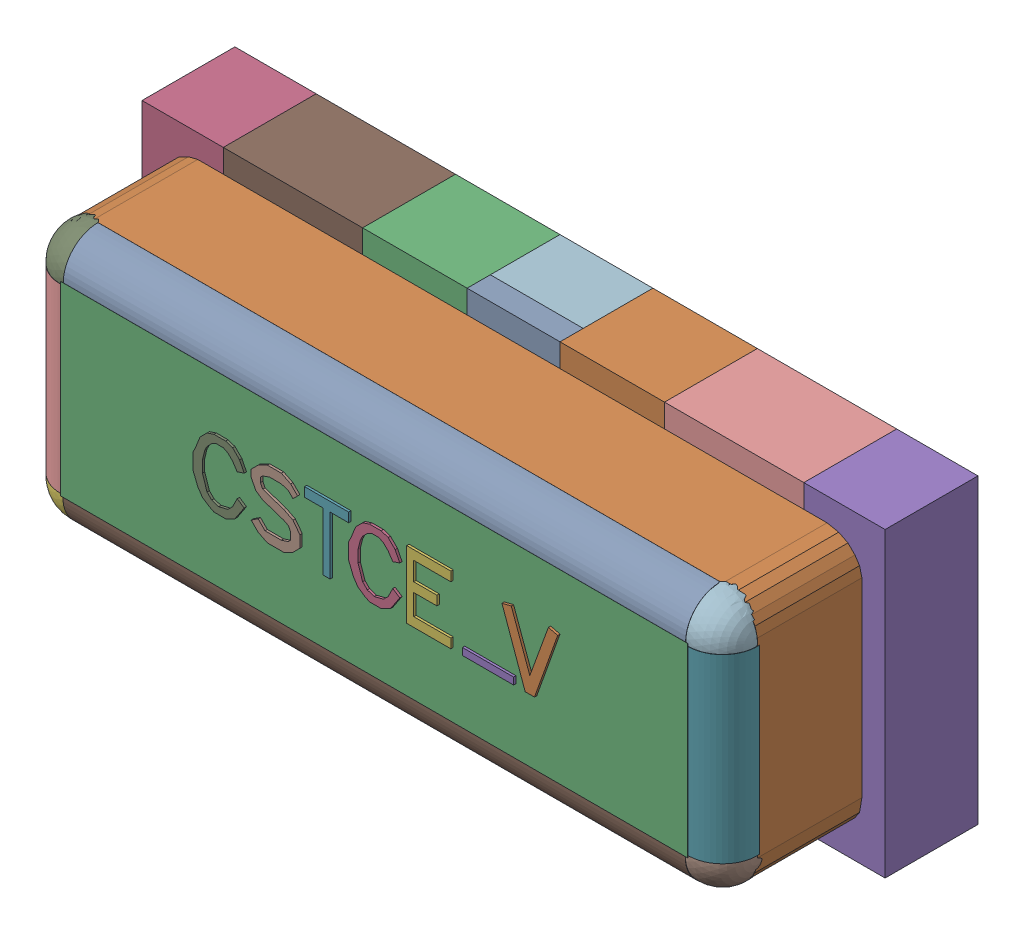
SolidWorks assembly User Library-Arduino Nano 3.0_User Library-CSTCE_V-1, configuration Default. Lengths in mm.
Overall size (3.2 1.3 1.12).
52 component instances, 17 part files, 0 mates.
Components (placement in the parent):
- User Library-Arduino Nano 3.0_User Library-CSTCE_V-1_Board1-1: User Library-Arduino Nano 3.0_User Library-CSTCE_V-1_Board1 [Default] at (0 0 -0.0938) size (0.01 0.01 0.11)
- User Library-Arduino Nano 3.0_User Library-CSTCE_V-1_Free-Models1-1: User Library-Arduino Nano 3.0_User Library-CSTCE_V-1_Free-Models1 [Default] at origin size (3.2 1.3 1.01)
  - User Library-Arduino Nano 3.0_User Library-CSTCE_V-1_453563857-1: User Library-Arduino Nano 3.0_User Library-CSTCE_V-1_453563857 [Default] at (1.63 0.025 1.0127) size (0.24 0.29 0.01)
    - User Library-Arduino Nano 3.0_User Library-CSTCE_V-1_Extruded20-1: User Library-Arduino Nano 3.0_User Library-CSTCE_V-1_Extruded20 [Default] at origin size (0.24 0.29 0.01)
  - User Library-Arduino Nano 3.0_User Library-CSTCE_V-1_453557585-1: User Library-Arduino Nano 3.0_User Library-CSTCE_V-1_453557585 [Default] at (0.95 0 0.8627) size (2.7 0.8 0.15)
    - User Library-Arduino Nano 3.0_User Library-CSTCE_V-1_Extruded15-1: User Library-Arduino Nano 3.0_User Library-CSTCE_V-1_Extruded15 [Default] at origin size (2.7 0.8 0.15)
  - User Library-Arduino Nano 3.0_User Library-CSTCE_V-1_453563985-1: User Library-Arduino Nano 3.0_User Library-CSTCE_V-1_453563985 [Default] at (0.96 0.025 1.0127) size (0.22 0.29 0.01)
    - User Library-Arduino Nano 3.0_User Library-CSTCE_V-1_Extruded14-1: User Library-Arduino Nano 3.0_User Library-CSTCE_V-1_Extruded14 [Default] at origin size (0.22 0.29 0.01)
  - User Library-Arduino Nano 3.0_User Library-CSTCE_V-1_453563601-1: User Library-Arduino Nano 3.0_User Library-CSTCE_V-1_453563601 [Default] at (1.45 -0.105 1.0127) size (0.22 0.03 0.01)
    - User Library-Arduino Nano 3.0_User Library-CSTCE_V-1_Extruded17-1: User Library-Arduino Nano 3.0_User Library-CSTCE_V-1_Extruded17 [Default] at origin size (0.22 0.03 0.01)
  - User Library-Arduino Nano 3.0_User Library-CSTCE_V-1_453565905-1: User Library-Arduino Nano 3.0_User Library-CSTCE_V-1_453565905 [Default] at (1.195 0.025 1.0127) size (0.19 0.29 0.01)
    - User Library-Arduino Nano 3.0_User Library-CSTCE_V-1_Extruded21-1: User Library-Arduino Nano 3.0_User Library-CSTCE_V-1_Extruded21 [Default] at origin size (0.19 0.29 0.01)
  - User Library-Arduino Nano 3.0_User Library-CSTCE_V-1_453566801-1: User Library-Arduino Nano 3.0_User Library-CSTCE_V-1_453566801 [Default] at (0.755 0.025 1.0127) size (0.19 0.29 0.01)
    - User Library-Arduino Nano 3.0_User Library-CSTCE_V-1_Extruded25-1: User Library-Arduino Nano 3.0_User Library-CSTCE_V-1_Extruded25 [Default] at origin size (0.19 0.29 0.01)
  - User Library-Arduino Nano 3.0_User Library-CSTCE_V-1_453567057-1: User Library-Arduino Nano 3.0_User Library-CSTCE_V-1_453567057 [Default] at (0.535 0.025 1.0127) size (0.21 0.29 0.01)
    - User Library-Arduino Nano 3.0_User Library-CSTCE_V-1_Extruded23-1: User Library-Arduino Nano 3.0_User Library-CSTCE_V-1_Extruded23 [Default] at origin size (0.21 0.29 0.01)
  - User Library-Arduino Nano 3.0_User Library-CSTCE_V-1_453563985-2: User Library-Arduino Nano 3.0_User Library-CSTCE_V-1_453563985 [Default] at (0.29 0.025 1.0127) size (0.22 0.29 0.01)
    - User Library-Arduino Nano 3.0_User Library-CSTCE_V-1_Extruded14-1: User Library-Arduino Nano 3.0_User Library-CSTCE_V-1_Extruded14 [Default] at origin size (0.22 0.29 0.01)
  - User Library-Arduino Nano 3.0_User Library-CSTCE_V-1_453562833-1: User Library-Arduino Nano 3.0_User Library-CSTCE_V-1_453562833 [Default] at (1.9 0 0.0127) size (0.6 1.3 0.4)
    - User Library-Arduino Nano 3.0_User Library-CSTCE_V-1_Extruded18-1: User Library-Arduino Nano 3.0_User Library-CSTCE_V-1_Extruded18 [Default] at origin size (0.6 1.3 0.4)
  - User Library-Arduino Nano 3.0_User Library-CSTCE_V-1_453562833-2: User Library-Arduino Nano 3.0_User Library-CSTCE_V-1_453562833 [Default] at (0 0 0.0127) size (0.6 1.3 0.4)
    - User Library-Arduino Nano 3.0_User Library-CSTCE_V-1_Extruded18-1: User Library-Arduino Nano 3.0_User Library-CSTCE_V-1_Extruded18 [Default] at origin size (0.6 1.3 0.4)
  - User Library-Arduino Nano 3.0_User Library-CSTCE_V-1_453562065-1: User Library-Arduino Nano 3.0_User Library-CSTCE_V-1_453562065 [Default] at (0.95 0 0.0127) size (0.4 1.3 0.3)
    - User Library-Arduino Nano 3.0_User Library-CSTCE_V-1_Extruded16-1: User Library-Arduino Nano 3.0_User Library-CSTCE_V-1_Extruded16 [Default] at origin size (0.4 1.3 0.3)
  - User Library-Arduino Nano 3.0_User Library-CSTCE_V-1_453566289-1: User Library-Arduino Nano 3.0_User Library-CSTCE_V-1_453566289 [Default] at (0.95 0 0.3127) size (0.4 1.3 0.1)
    - User Library-Arduino Nano 3.0_User Library-CSTCE_V-1_Extruded13-1: User Library-Arduino Nano 3.0_User Library-CSTCE_V-1_Extruded13 [Default] at origin size (0.4 1.3 0.1)
  - User Library-Arduino Nano 3.0_User Library-CSTCE_V-1_453565777-1: User Library-Arduino Nano 3.0_User Library-CSTCE_V-1_453565777 [Default] at (1.375 0 0.0127) size (0.45 1.3 0.4)
    - User Library-Arduino Nano 3.0_User Library-CSTCE_V-1_Extruded24-1: User Library-Arduino Nano 3.0_User Library-CSTCE_V-1_Extruded24 [Default] at origin size (0.45 1.3 0.4)
  - User Library-Arduino Nano 3.0_User Library-CSTCE_V-1_453565777-2: User Library-Arduino Nano 3.0_User Library-CSTCE_V-1_453565777 [Default] at (0.525 0 0.0127) size (0.45 1.3 0.4)
    - User Library-Arduino Nano 3.0_User Library-CSTCE_V-1_Extruded24-1: User Library-Arduino Nano 3.0_User Library-CSTCE_V-1_Extruded24 [Default] at origin size (0.45 1.3 0.4)
  - User Library-Arduino Nano 3.0_User Library-CSTCE_V-1_453563729-1: User Library-Arduino Nano 3.0_User Library-CSTCE_V-1_453563729 [Default] at (-0.475 0 0.0127) size (0.35 1.3 0.4)
    - User Library-Arduino Nano 3.0_User Library-CSTCE_V-1_Extruded22-1: User Library-Arduino Nano 3.0_User Library-CSTCE_V-1_Extruded22 [Default] at origin size (0.35 1.3 0.4)
  - User Library-Arduino Nano 3.0_User Library-CSTCE_V-1_453563729-2: User Library-Arduino Nano 3.0_User Library-CSTCE_V-1_453563729 [Default] at (2.375 0 0.0127) size (0.35 1.3 0.4)
    - User Library-Arduino Nano 3.0_User Library-CSTCE_V-1_Extruded22-1: User Library-Arduino Nano 3.0_User Library-CSTCE_V-1_Extruded22 [Default] at origin size (0.35 1.3 0.4)
  - User Library-Arduino Nano 3.0_User Library-CSTCE_V-1_453330369-1: User Library-Arduino Nano 3.0_User Library-CSTCE_V-1_453330369 [Default] at (-0.4016 -0.4006 0.8627) size (0.3 0.3 0.3)
    - User Library-Arduino Nano 3.0_User Library-CSTCE_V-1_Sphere1-1: User Library-Arduino Nano 3.0_User Library-CSTCE_V-1_Sphere1 [Default] at origin size (0.3 0.3 0.3)
  - User Library-Arduino Nano 3.0_User Library-CSTCE_V-1_453331489-1: User Library-Arduino Nano 3.0_User Library-CSTCE_V-1_453331489 [Default] at (2.3004 0.3894 0.8627) x (1 0 0) z (0 -1 0) size (0.3 0.3 0.78)
    - User Library-Arduino Nano 3.0_User Library-CSTCE_V-1_Cylinder3-1: User Library-Arduino Nano 3.0_User Library-CSTCE_V-1_Cylinder3 [Default] at origin size (0.3 0.3 0.78)
  - User Library-Arduino Nano 3.0_User Library-CSTCE_V-1_453330369-2: User Library-Arduino Nano 3.0_User Library-CSTCE_V-1_453330369 [Default] at (2.3 -0.4006 0.8627) size (0.3 0.3 0.3)
    - User Library-Arduino Nano 3.0_User Library-CSTCE_V-1_Sphere1-1: User Library-Arduino Nano 3.0_User Library-CSTCE_V-1_Sphere1 [Default] at origin size (0.3 0.3 0.3)
  - User Library-Arduino Nano 3.0_User Library-CSTCE_V-1_453330369-3: User Library-Arduino Nano 3.0_User Library-CSTCE_V-1_453330369 [Default] at (-0.4016 0.4006 0.8627) size (0.3 0.3 0.3)
    - User Library-Arduino Nano 3.0_User Library-CSTCE_V-1_Sphere1-1: User Library-Arduino Nano 3.0_User Library-CSTCE_V-1_Sphere1 [Default] at origin size (0.3 0.3 0.3)
  - User Library-Arduino Nano 3.0_User Library-CSTCE_V-1_453331489-2: User Library-Arduino Nano 3.0_User Library-CSTCE_V-1_453331489 [Default] at (-0.4016 0.3894 0.8627) x (1 0 0) z (0 -1 0) size (0.3 0.3 0.78)
    - User Library-Arduino Nano 3.0_User Library-CSTCE_V-1_Cylinder3-1: User Library-Arduino Nano 3.0_User Library-CSTCE_V-1_Cylinder3 [Default] at origin size (0.3 0.3 0.78)
  - User Library-Arduino Nano 3.0_User Library-CSTCE_V-1_453331041-1: User Library-Arduino Nano 3.0_User Library-CSTCE_V-1_453331041 [Default] at (-0.3908 -0.4013 0.8627) x (0 1 0) z (1 0 0) size (0.3 0.3 2.68)
    - User Library-Arduino Nano 3.0_User Library-CSTCE_V-1_Cylinder2-1: User Library-Arduino Nano 3.0_User Library-CSTCE_V-1_Cylinder2 [Default] at origin size (0.3 0.3 2.68)
  - User Library-Arduino Nano 3.0_User Library-CSTCE_V-1_453330369-4: User Library-Arduino Nano 3.0_User Library-CSTCE_V-1_453330369 [Default] at (2.3 0.4006 0.8627) size (0.3 0.3 0.3)
    - User Library-Arduino Nano 3.0_User Library-CSTCE_V-1_Sphere1-1: User Library-Arduino Nano 3.0_User Library-CSTCE_V-1_Sphere1 [Default] at origin size (0.3 0.3 0.3)
  - User Library-Arduino Nano 3.0_User Library-CSTCE_V-1_453331041-2: User Library-Arduino Nano 3.0_User Library-CSTCE_V-1_453331041 [Default] at (-0.3892 0.4001 0.8627) x (0 1 0) z (1 0 0) size (0.3 0.3 2.68)
    - User Library-Arduino Nano 3.0_User Library-CSTCE_V-1_Cylinder2-1: User Library-Arduino Nano 3.0_User Library-CSTCE_V-1_Cylinder2 [Default] at origin size (0.3 0.3 2.68)
  - User Library-Arduino Nano 3.0_User Library-CSTCE_V-1_453565521-1: User Library-Arduino Nano 3.0_User Library-CSTCE_V-1_453565521 [Default] at (0.95 0 0.4127) size (3 1.1 0.45)
    - User Library-Arduino Nano 3.0_User Library-CSTCE_V-1_Extruded19-1: User Library-Arduino Nano 3.0_User Library-CSTCE_V-1_Extruded19 [Default] at origin size (3 1.1 0.45)
